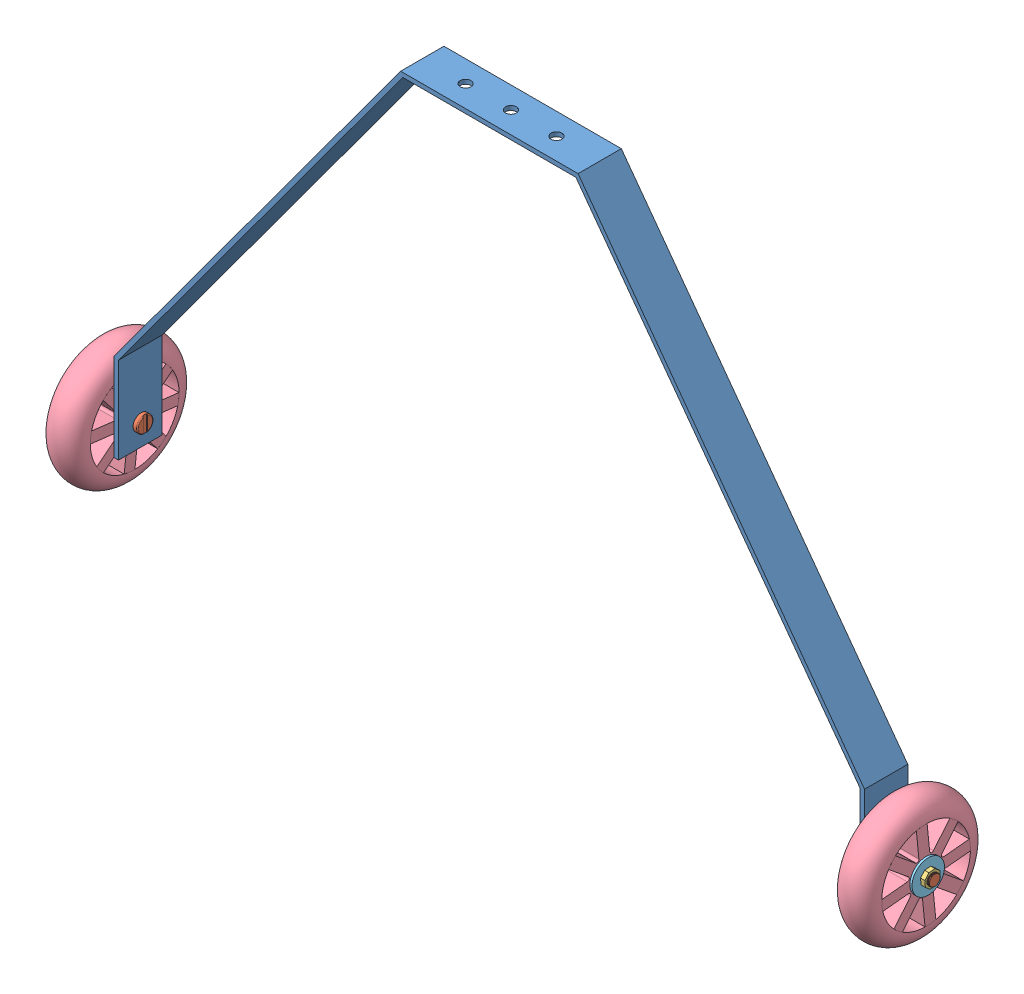
SolidWorks assembly Main gear assembly, configuration Default. Lengths in mm.
Overall size (390.85 251.73 81.62).
11 component instances, 5 part files, 20 mates.
Components (placement in the parent):
- Main Gear-1: Main Gear [Default] at (56.8356 250.9419 269.2629) size (346.85 220.92 20)
- Bolt-1: Bolt [Default] at (265.5864 107.4488 278.7975) x (0 0.8029 0.596114) z (-1 0 0) size (7.5 7.5 26.03)
- Nut-1: Nut [Default] at (262.5864 107.4488 278.7975) x (1 0 0) z (0 0.308408 0.951254) size (2 7.5 7.5)
- Tire-1: Tire [Default] at (244.5864 107.4488 278.7975) x (0 -0.633726 -0.773558) z (0 -0.773558 0.633726) size (58 17 58)
- Washer-1: Washer [Default] at (243.5864 107.4488 278.7975) size (1 15 15)
- Washer-2: Washer [Default] at (261.5864 107.4488 278.7975) x (1 0 0) z (0 -0.986827 0.16178) size (1 15 15)
- Bolt-2: Bolt [Default] at (-125.2675 107.4488 278.7975) x (0 0 -1) z (1 0 0) size (7.5 7.5 26.03)
- Nut-2: Nut [Default] at (-124.2675 107.4488 278.7975) size (2 7.5 7.5)
- Tire-2: Tire [Default] at (-121.2675 107.4488 278.7975) x (0 -0.618786 0.78556) z (0 0.78556 0.618786) size (58 17 58)
- Washer-3: Washer [Default] at (-104.2675 107.4488 278.7975) size (1 15 15)
- Washer-4: Washer [Default] at (-122.2675 107.4488 278.7975) size (1 15 15)
Mates (geometry in assembly coordinates):
- Concentric1: concentric aligned: cylinder of Main Gear-1 through (333.5864 107.4488 278.7975) axis (-1 0 0) radius 2.5; cylinder of Washer-1 through (244.5864 107.4488 278.7975) axis (-1 0 0) radius 2.5
- Coincident1: coincident anti-aligned: plane of Main Gear-1 through (243.5864 97.4488 289.2629) normal (1 0 0); plane of Washer-1 through (243.5864 107.4488 278.7975) normal (-1 0 0)
- Concentric2: concentric anti-aligned: cylinder of Tire-1 through (244.5864 107.4488 278.7975) axis (1 0 0) radius 2.5; cylinder of Washer-1 through (244.5864 107.4488 278.7975) axis (-1 0 0) radius 2.5
- Coincident2: coincident anti-aligned: plane of Tire-1 through (244.5864 107.4488 278.7975) normal (-1 0 0); plane of Washer-1 through (244.5864 107.4488 278.7975) normal (1 0 0)
- Concentric3: concentric anti-aligned: cylinder of Main Gear-1 through (333.5864 107.4488 278.7975) axis (-1 0 0) radius 2.5; cylinder of Bolt-1 through (241.5864 107.4488 278.7975) axis (1 0 0) radius 2.5
- Concentric4: concentric: cylinder of Tire-1 through (244.5864 107.4488 278.7975) axis (1 0 0) radius 2.5; cylinder of Washer-2 through (262.5864 107.4488 278.7975) axis (-1 0 0) radius 2.5
- Coincident6: coincident anti-aligned: plane of Tire-1 through (261.5864 107.4488 278.7975) normal (1 0 0); plane of Washer-2 through (261.5864 107.4488 278.7975) normal (-1 0 0)
- Concentric5: concentric anti-aligned: circle of Nut-1; cylinder of Washer-2 through (262.5864 107.4488 278.7975) axis (-1 0 0) radius 2.5
- Coincident8: coincident: plane of Nut-1 through (262.5864 107.4488 278.7975) normal (-1 0 0); plane of Washer-2 through (262.5864 107.4488 278.7975) normal (1 0 0)
- Coincident9: coincident anti-aligned: plane of Main Gear-1 through (241.5864 137.4488 289.2629) normal (-1 0 0); plane of Bolt-1 through (241.5864 107.4488 278.7975) normal (1 0 0)
- Concentric6: concentric aligned: cylinder of Main Gear-1 through (333.5864 107.4488 278.7975) axis (-1 0 0) radius 2.5; cylinder of Washer-3 through (-103.2675 107.4488 278.7975) axis (-1 0 0) radius 2.5
- Coincident10: coincident anti-aligned: plane of Main Gear-1 through (-103.2675 138.1044 289.2629) normal (-1 0 0); plane of Washer-3 through (-103.2675 107.4488 278.7975) normal (1 0 0)
- Concentric7: concentric anti-aligned: cylinder of Tire-2 through (-121.2675 107.4488 278.7975) axis (1 0 0) radius 2.5; cylinder of Washer-3 through (-103.2675 107.4488 278.7975) axis (-1 0 0) radius 2.5
- Coincident11: coincident: plane of Washer-3 through (-104.2675 107.4488 278.7975) normal (-1 0 0); plane of Tire-2 through (-104.2675 107.4488 278.7975) normal (1 0 0)
- Concentric8: concentric aligned: circle of Nut-2; cylinder of Tire-2 through (-121.2675 107.4488 278.7975) axis (1 0 0) radius 2.5
- Concentric9: concentric anti-aligned: cylinder of Tire-2 through (-121.2675 107.4488 278.7975) axis (1 0 0) radius 2.5; cylinder of Washer-4 through (-121.2675 107.4488 278.7975) axis (-1 0 0) radius 2.5
- Coincident14: coincident anti-aligned: plane of Tire-2 through (-121.2675 107.4488 278.7975) normal (-1 0 0); plane of Washer-4 through (-121.2675 107.4488 278.7975) normal (1 0 0)
- Coincident15: coincident anti-aligned: plane of Nut-2 through (-122.2675 107.4488 278.7975) normal (1 0 0); plane of Washer-4 through (-122.2675 107.4488 278.7975) normal (-1 0 0)
- Concentric11: concentric anti-aligned: cylinder of Bolt-2 through (-101.2675 107.4488 278.7975) axis (-1 0 0) radius 2.5; circle of Tire-2
- Coincident19: coincident anti-aligned: plane of Main Gear-1 through (-101.2675 97.4488 289.2629) normal (1 0 0); plane of Bolt-2 through (-101.2675 107.4488 278.7975) normal (-1 0 0)
